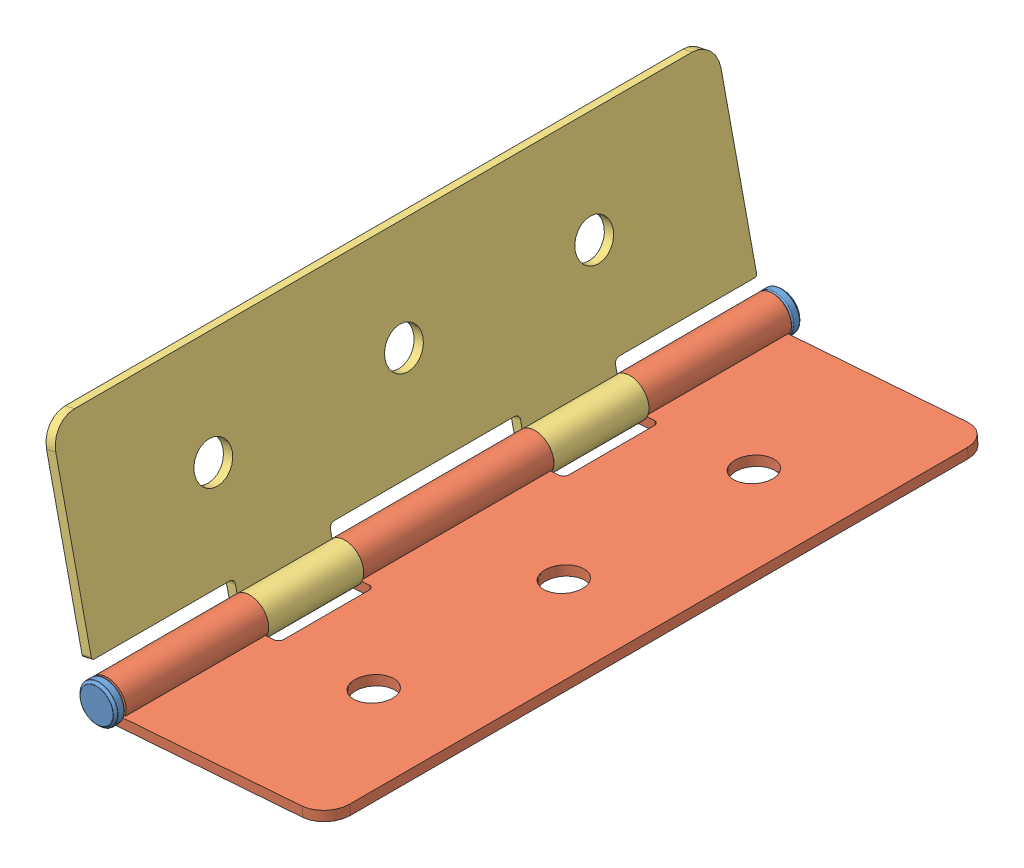
SolidWorks assembly Hinge Assembly hyujgjuyh, configuration Default. Lengths in mm.
Overall size (60.04 50.55 144.5).
3 component instances, 3 part files, 4 mates.
Components (placement in the parent):
- part 3-1: part 3 [Default] at origin size (8 8 144.5)
- Part 1-1: Part 1 [Default] at (46.0224 1.391 70) x (0 0 -1) z (-0.073599 0.997288 0) size (140 50 8)
- part 2-1: part 2 [Default] at (-11.9144 44.4752 -70) x (0 0 1) z (0.976269 0.216562 0) size (140 50 8)
Mates (geometry in assembly coordinates):
- Concentric2: concentric anti-aligned: cylinder of part 3-1 through (0 0 70.25) axis (0 0 -1) radius 1.85; cylinder of Part 1-1 through (0 0 -40) axis (0 0 1) radius 2
- Width1: width anti-aligned: plane of part 3-1 through (0 0 70.25) normal (0 0 -1); plane of Part 1-1 through (0 0 -70.25) normal (0 0 1); plane of part 3-1 through (0 0 20) normal (0 0 1); plane of Part 1-1 through (0 0 -20) normal (0 0 -1)
- Concentric4: concentric aligned: cylinder of part 3-1 through (0 0 70.25) axis (0 0 -1) radius 1.85; cylinder of part 2-1 through (0 0 -40) axis (0 0 -1) radius 2
- Coincident4: coincident anti-aligned: plane of Part 1-1 through (0 0 40) normal (0 0 -1); plane of part 2-1 through (0 0 40) normal (0 0 1)
